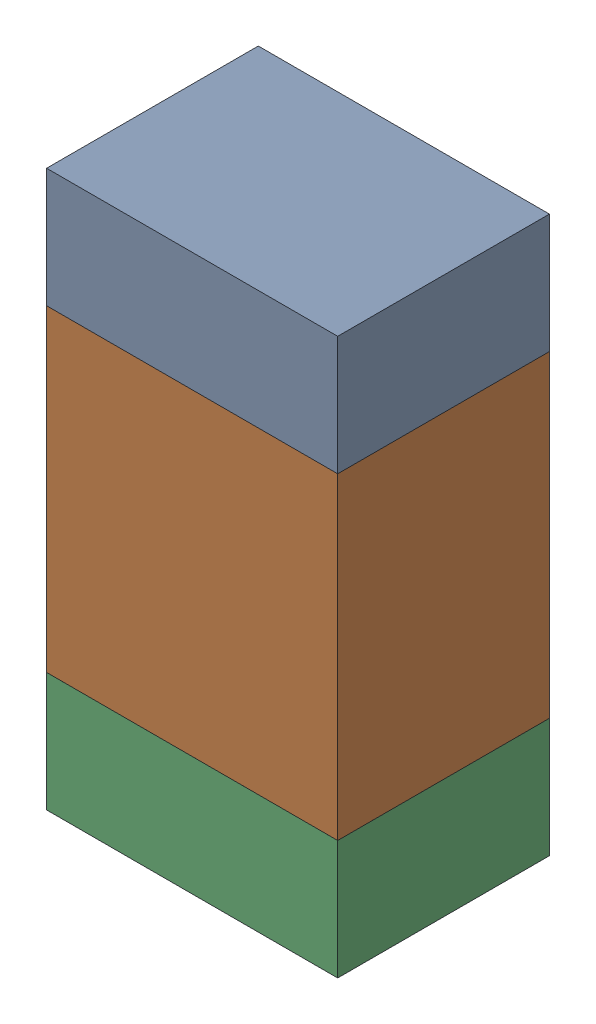
SolidWorks assembly R107_1PCB, configuration Default. Lengths in mm.
Overall size (0.55 1.05 0.4).
6 component instances, 2 part files, 0 mates.
Components (placement in the parent):
- 846483288-1: 846483288 [Default] at (115.1001 121.6624 0) size (0.55 0.22 0.4)
  - Extruded_12-1: Extruded_12 [Default] at origin size (0.55 0.22 0.4)
- 846483424-1: 846483424 [Default] at (115.1001 121.2499 0) size (0.55 0.6 0.4)
  - Extruded_13-1: Extruded_13 [Default] at origin size (0.55 0.6 0.4)
- 846483288-2: 846483288 [Default] at (115.1001 120.8374 0) size (0.55 0.22 0.4)
  - Extruded_12-1: Extruded_12 [Default] at origin size (0.55 0.22 0.4)
